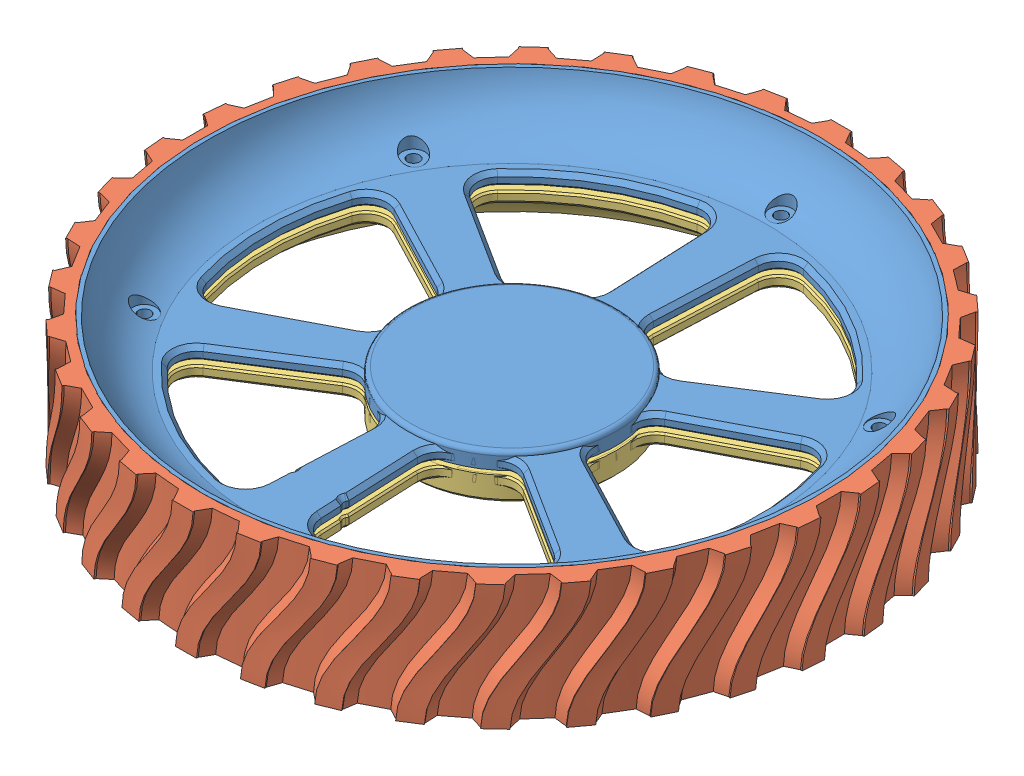
SolidWorks assembly big_bilbo_wheel, configuration Default. Lengths in mm.
Overall size (157.8 30.1 157.96).
3 component instances, 3 part files, 4 mates.
Components (placement in the parent):
- wheel_big_bilbo_outer-1: wheel_big_bilbo_outer [Default] at origin size (148 14.5 148)
- treads-1: treads [Default] at (0 -0.5 0) size (157.8 30.1 157.96)
- wheel_big_bilbo_inner-1: wheel_big_bilbo_inner [Default] at (0 -1 0) size (148 14.5 148)
Mates (geometry in assembly coordinates):
- Concentric1: concentric aligned: circle of wheel_big_bilbo_outer-1; circle of treads-1
- Coincident1: coincident aligned: plane of wheel_big_bilbo_outer-1; plane of treads-1 through (0 14.5 -74) normal (0 1 0)
- Coincident2: coincident anti-aligned: circle of treads-1; circle of wheel_big_bilbo_inner-1
- Concentric2: concentric aligned: circle of wheel_big_bilbo_outer-1; circle of wheel_big_bilbo_inner-1
